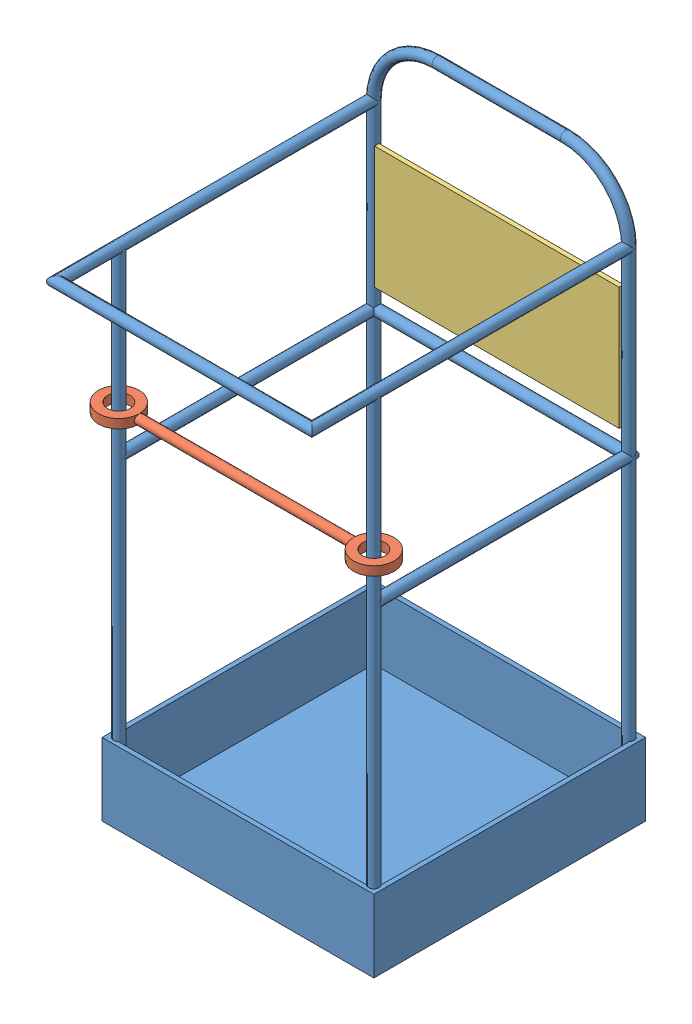
SolidWorks assembly 01, configuration Default. Lengths in mm.
Overall size (653 1251.5 730).
3 component instances, 3 part files, 5 mates.
Components (placement in the parent):
- base-1: base [Default] at (-695.0621 -529.7128 425.7796) size (600 1251.5 730)
- gaurd-1: gaurd [Default] at (-641.5621 261.6954 407.2796) x (0 0 -1) z (1 0 0) size (90 20 653)
- Part1-1: Part1 [Default] at (-395.0621 355.2872 -155.7204) size (540 270 10)
Mates (geometry in assembly coordinates):
- Concentric10: concentric aligned: cylinder of base-1 through (-676.5621 170.2872 407.2796) axis (0 -1 0) radius 11.5; cylinder of gaurd-1 through (-676.5621 261.6954 407.2796) axis (0 -1 0) radius 25
- Concentric11: concentric aligned: cylinder of base-1 through (-113.5621 170.2872 407.2796) axis (0 -1 0) radius 11.5; cylinder of gaurd-1 through (-113.5621 261.6954 407.2796) axis (0 -1 0) radius 25
- Coincident1: coincident: cylinder of base-1 through (-676.5621 570.2872 -155.7204) axis (0 -1 0) radius 11.5; line of Part1-1 through (-665.0621 490.2872 -155.7204) axis (0 -1 0)
- Coincident2: coincident: cylinder of base-1 through (-113.5621 570.2872 -155.7204) axis (0 -1 0) radius 11.5; line of Part1-1 through (-125.0621 220.2872 -155.7204) axis (0 1 0)
- Distance1: distance = 740 mm anti-aligned: plane of Part1-1 through (-665.0621 220.2872 -145.7204) normal (0 -1 0); plane of base-1 through (-695.0621 -519.7128 425.7796) normal (0 1 0)
